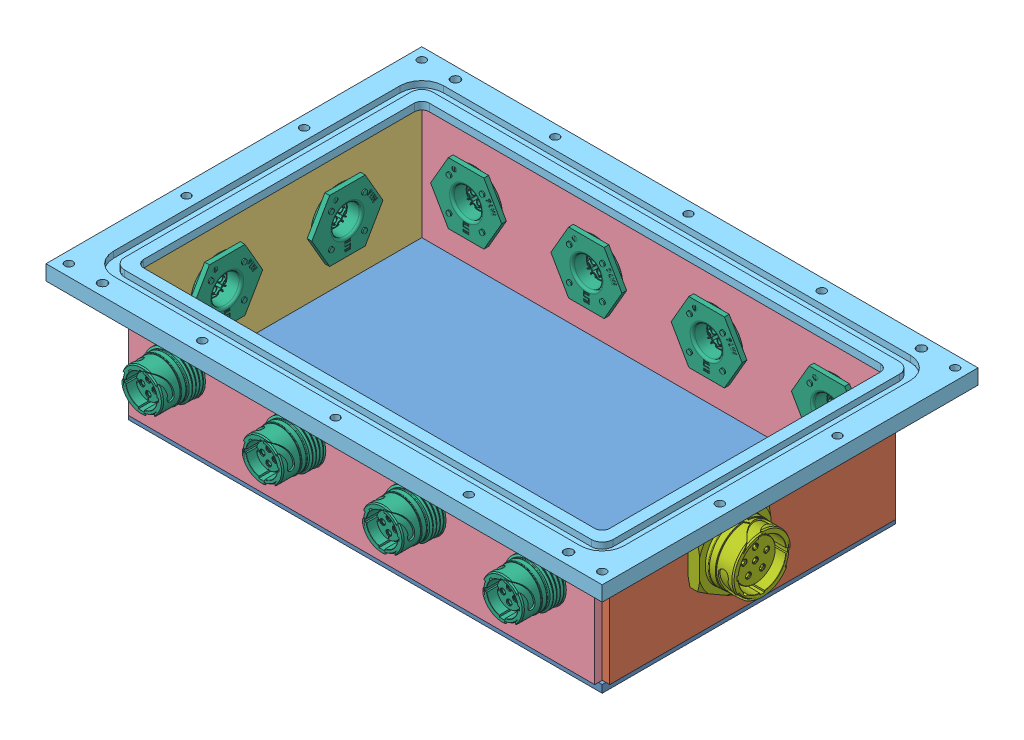
SolidWorks assembly A. Power Distribution Box Welded, configuration Default. Lengths in mm.
Overall size (237.68 57.15 161.39).
17 component instances, 7 part files, 46 mates.
Components (placement in the parent):
- Power Distribution Box Bottom-1: Power Distribution Box Bottom [Default] at (106.4097 88.1405 149.8512) size (200.03 6.35 123.83)
- Power Distribution Box Front Plate-1: Power Distribution Box Front Plate [Default] at (306.4347 91.3155 149.8512) size (3.17 50.8 120.65)
- Power Distribution Box Back Plate-1: Power Distribution Box Back Plate [Default] at (-93.6153 91.3155 149.8512) size (3.17 50.8 120.65)
- Power Distribution Box Side Plate-1: Power Distribution Box Side Plate [Default] at (106.4097 91.3155 149.8512) size (196.85 50.8 3.18)
- Power Distribution Box Side Plate-2: Power Distribution Box Side Plate [Default] at (106.4097 91.3155 26.0262) size (196.85 50.8 3.18)
- Power Distribution Box Flange-1: Power Distribution Box Flange [Default] at (106.4097 138.9405 149.8512) size (234.95 6.35 158.75)
- Samtec ACR 16 Recepticle-1: Samtec ACR 16 Recepticle [Default] at (30.2097 119.8905 230.1762) x (-1 0 0) z (0 0 1) size (30.02 26 24.37)
- Samtec ACR 16 Recepticle-2: Samtec ACR 16 Recepticle [Default] at (-12.0153 119.8905 175.2512) x (0 0 -1) z (-1 0 0) size (30.02 26 24.37)
- Samtec ACR 16 Recepticle-3: Samtec ACR 16 Recepticle [Default] at (30.2097 119.8905 69.5262) x (1 0 0) z (0 0 -1) size (30.02 26 24.37)
- Samtec ACR 16 Recepticle-4: Samtec ACR 16 Recepticle [Default] at (81.0097 119.8905 230.1762) x (-1 0 0) z (0 0 1) size (30.02 26 24.37)
- Samtec ACR 16 Recepticle-5: Samtec ACR 16 Recepticle [Default] at (131.8097 119.8905 230.1762) x (-1 0 0) z (0 0 1) size (30.02 26 24.37)
- Samtec ACR 16 Recepticle-6: Samtec ACR 16 Recepticle [Default] at (182.6097 119.8905 230.1762) x (-1 0 0) z (0 0 1) size (30.02 26 24.37)
- Samtec ACR 16 Recepticle-7: Samtec ACR 16 Recepticle [Default] at (81.0097 119.8905 69.5262) x (1 0 0) z (0 0 -1) size (30.02 26 24.37)
- Samtec ACR 16 Recepticle-8: Samtec ACR 16 Recepticle [Default] at (131.8097 119.8905 69.5262) x (1 0 0) z (0 0 -1) size (30.02 26 24.37)
- Samtec ACR 16 Recepticle-9: Samtec ACR 16 Recepticle [Default] at (182.6097 119.8905 69.5262) x (1 0 0) z (0 0 -1) size (30.02 26 24.37)
- Samtec ACR 16 Recepticle-10: Samtec ACR 16 Recepticle [Default] at (-12.0153 119.8905 124.4512) x (0 0 -1) z (-1 0 0) size (30.02 26 24.37)
- Samtec ACR 22-1: Samtec ACR 22 [Default] at (224.8347 119.8905 162.5512) x (0 0 -1) z (1 0 0) size (38.11 34.64 24.46)
Mates (geometry in assembly coordinates):
- Coincident1: coincident anti-aligned: plane of Power Distribution Box Bottom-1 through (204.8347 94.4905 210.1762) normal (1 0 0); plane of Power Distribution Box Front Plate-1 through (204.8347 142.1155 210.1762) normal (-1 0 0)
- Coincident2: coincident anti-aligned: plane of Power Distribution Box Bottom-1 through (106.4097 91.3155 149.8512) normal (0 1 0); plane of Power Distribution Box Front Plate-1 through (306.4347 91.3155 149.8512) normal (0 -1 0)
- Coincident3: coincident anti-aligned: plane of Power Distribution Box Side Plate-2 through (106.4097 91.3155 26.0262) normal (0 -1 0); plane of Power Distribution Box Bottom-1 through (106.4097 91.3155 149.8512) normal (0 1 0)
- Coincident4: coincident anti-aligned: plane of Power Distribution Box Bottom-1 through (204.8347 94.4905 89.5262) normal (0 0 -1); plane of Power Distribution Box Side Plate-2 through (208.0097 142.1155 89.5262) normal (0 0 1)
- Coincident5: coincident anti-aligned: line of Power Distribution Box Front Plate-1 through (204.8347 142.1155 89.5262) axis (0 -1 0); line of Power Distribution Box Side Plate-2 through (204.8347 91.3155 89.5262) axis (0 1 0)
- Coincident6: coincident anti-aligned: line of Power Distribution Box Back Plate-1 through (7.9847 142.1155 89.5262) axis (0 -1 0); line of Power Distribution Box Side Plate-2 through (7.9847 91.3155 89.5262) axis (0 1 0)
- Coincident7: coincident anti-aligned: plane of Power Distribution Box Bottom-1 through (106.4097 91.3155 149.8512) normal (0 1 0); plane of Power Distribution Box Back Plate-1 through (-93.6153 91.3155 149.8512) normal (0 -1 0)
- Coincident8: coincident anti-aligned: plane of Power Distribution Box Bottom-1 through (7.9847 94.4905 89.5262) normal (-1 0 0); plane of Power Distribution Box Back Plate-1 through (7.9847 142.1155 210.1762) normal (1 0 0)
- Coincident9: coincident anti-aligned: line of Power Distribution Box Back Plate-1 through (7.9847 142.1155 210.1762) axis (0 -1 0); line of Power Distribution Box Side Plate-1 through (7.9847 91.3155 210.1762) axis (0 1 0)
- Coincident10: coincident anti-aligned: plane of Power Distribution Box Bottom-1 through (106.4097 91.3155 149.8512) normal (0 1 0); plane of Power Distribution Box Side Plate-1 through (106.4097 91.3155 149.8512) normal (0 -1 0)
- Coincident11: coincident anti-aligned: plane of Power Distribution Box Bottom-1 through (7.9847 94.4905 210.1762) normal (0 0 1); plane of Power Distribution Box Side Plate-1 through (7.9847 91.3155 210.1762) normal (0 0 -1)
- Coincident12: coincident anti-aligned: plane of Power Distribution Box Side Plate-1 through (106.4097 142.1155 149.8512) normal (0 1 0); plane of Power Distribution Box Flange-1 through (106.4097 142.1155 149.8512) normal (0 -1 0)
- Coincident13: coincident anti-aligned: plane of Power Distribution Box Side Plate-1 through (208.0097 142.1155 213.3512) normal (0 0 1); plane of Power Distribution Box Flange-1 through (208.0097 142.1155 213.3512) normal (0 0 -1)
- Coincident14: coincident anti-aligned: plane of Power Distribution Box Back Plate-1 through (4.8097 91.3155 207.0012) normal (-1 0 0); plane of Power Distribution Box Flange-1 through (4.8097 142.1155 213.3512) normal (1 0 0)
- Concentric6: concentric anti-aligned: cylinder of Power Distribution Box Side Plate-1 through (30.2097 119.8905 86.3512) axis (0 0 1) radius 10.2489; cylinder of Samtec ACR 16 Recepticle-1 through (30.2097 119.8905 230.1762) axis (0 0 -1) radius 8.75
- Parallel4: parallel anti-aligned: plane of Power Distribution Box Side Plate-1 through (106.4097 111.1529 86.3512) normal (0 1 0); plane of Samtec ACR 16 Recepticle-1 through (34.7677 111.1405 230.5464) normal (0 -1 0)
- Tangent2: tangent: plane of Power Distribution Box Side Plate-1 through (7.9847 91.3155 210.1762) normal (0 0 -1); torus of Samtec ACR 16 Recepticle-1
- Concentric8: concentric aligned: cylinder of Power Distribution Box Back Plate-1 through (-195.2163 119.8905 175.2512) axis (1 0 0) radius 10.2489; cylinder of Samtec ACR 16 Recepticle-2 through (-12.0153 119.8905 175.2512) axis (1 0 0) radius 8.75
- Parallel6: parallel anti-aligned: plane of Power Distribution Box Back Plate-1 through (-195.2163 111.1529 149.8512) normal (0 1 0); plane of Samtec ACR 16 Recepticle-2 through (-12.3855 111.1405 179.8092) normal (0 -1 0)
- Tangent4: tangent: plane of Power Distribution Box Back Plate-1 through (7.9847 142.1155 210.1762) normal (1 0 0); torus of Samtec ACR 16 Recepticle-2
- Concentric9: concentric aligned: cylinder of Power Distribution Box Side Plate-2 through (30.2097 119.8905 -37.4738) axis (0 0 1) radius 10.2489; cylinder of Samtec ACR 16 Recepticle-3 through (30.2097 119.8905 69.5262) axis (0 0 1) radius 8.75
- Parallel7: parallel anti-aligned: plane of Power Distribution Box Side Plate-2 through (106.4097 111.1529 -37.4738) normal (0 1 0); plane of Samtec ACR 16 Recepticle-3 through (25.6517 111.1405 69.1559) normal (0 -1 0)
- Tangent5: tangent: plane of Power Distribution Box Side Plate-2 through (208.0097 142.1155 89.5262) normal (0 0 1); torus of Samtec ACR 16 Recepticle-3
- Concentric10: concentric anti-aligned: cylinder of Power Distribution Box Side Plate-1 through (81.0097 119.8905 86.3512) axis (0 0 1) radius 10.2489; cylinder of Samtec ACR 16 Recepticle-4 through (81.0097 119.8905 230.1762) axis (0 0 -1) radius 8.75
- Parallel8: parallel anti-aligned: plane of Power Distribution Box Side Plate-1 through (106.4097 111.1529 86.3512) normal (0 1 0); plane of Samtec ACR 16 Recepticle-4 through (85.5677 111.1405 230.5464) normal (0 -1 0)
- Tangent6: tangent: plane of Power Distribution Box Side Plate-1 through (7.9847 91.3155 210.1762) normal (0 0 -1); torus of Samtec ACR 16 Recepticle-4
- Tangent7: tangent: plane of Power Distribution Box Side Plate-1 through (7.9847 91.3155 210.1762) normal (0 0 -1); torus of Samtec ACR 16 Recepticle-5
- Concentric11: concentric anti-aligned: cylinder of Power Distribution Box Side Plate-1 through (131.8097 119.8905 86.3512) axis (0 0 1) radius 10.2489; cylinder of Samtec ACR 16 Recepticle-5 through (131.8097 119.8905 230.1762) axis (0 0 -1) radius 8.75
- Parallel9: parallel anti-aligned: plane of Power Distribution Box Side Plate-1 through (106.4097 111.1529 86.3512) normal (0 1 0); plane of Samtec ACR 16 Recepticle-5 through (136.3677 111.1405 230.5464) normal (0 -1 0)
- Tangent8: tangent: plane of Power Distribution Box Side Plate-1 through (7.9847 91.3155 210.1762) normal (0 0 -1); torus of Samtec ACR 16 Recepticle-6
- Concentric12: concentric anti-aligned: cylinder of Power Distribution Box Side Plate-1 through (182.6097 119.8905 86.3512) axis (0 0 1) radius 10.2489; cylinder of Samtec ACR 16 Recepticle-6 through (182.6097 119.8905 230.1762) axis (0 0 -1) radius 8.75
- Parallel10: parallel anti-aligned: plane of Power Distribution Box Side Plate-1 through (106.4097 111.1529 86.3512) normal (0 1 0); plane of Samtec ACR 16 Recepticle-6 through (187.1677 111.1405 230.5464) normal (0 -1 0)
- Concentric13: concentric aligned: cylinder of Power Distribution Box Side Plate-2 through (81.0097 119.8905 -37.4738) axis (0 0 1) radius 10.2489; cylinder of Samtec ACR 16 Recepticle-7 through (81.0097 119.8905 69.5262) axis (0 0 1) radius 8.75
- Parallel11: parallel anti-aligned: plane of Power Distribution Box Side Plate-2 through (106.4097 111.1529 -37.4738) normal (0 1 0); plane of Samtec ACR 16 Recepticle-7 through (76.4517 111.1405 69.1559) normal (0 -1 0)
- Tangent9: tangent: plane of Power Distribution Box Side Plate-2 through (208.0097 142.1155 89.5262) normal (0 0 1); torus of Samtec ACR 16 Recepticle-7
- Tangent10: tangent: plane of Power Distribution Box Side Plate-2 through (208.0097 142.1155 89.5262) normal (0 0 1); torus of Samtec ACR 16 Recepticle-8
- Concentric14: concentric aligned: cylinder of Power Distribution Box Side Plate-2 through (131.8097 119.8905 -37.4738) axis (0 0 1) radius 10.2489; cylinder of Samtec ACR 16 Recepticle-8 through (131.8097 119.8905 69.5262) axis (0 0 1) radius 8.75
- Parallel12: parallel anti-aligned: plane of Power Distribution Box Side Plate-2 through (106.4097 111.1529 -37.4738) normal (0 1 0); plane of Samtec ACR 16 Recepticle-8 through (127.2517 111.1405 69.1559) normal (0 -1 0)
- Tangent11: tangent: plane of Power Distribution Box Side Plate-2 through (208.0097 142.1155 89.5262) normal (0 0 1); torus of Samtec ACR 16 Recepticle-9
- Concentric15: concentric aligned: cylinder of Power Distribution Box Side Plate-2 through (182.6097 119.8905 -37.4738) axis (0 0 1) radius 10.2489; cylinder of Samtec ACR 16 Recepticle-9 through (182.6097 119.8905 69.5262) axis (0 0 1) radius 8.75
- Parallel13: parallel anti-aligned: plane of Power Distribution Box Side Plate-2 through (106.4097 111.1529 -37.4738) normal (0 1 0); plane of Samtec ACR 16 Recepticle-9 through (178.0517 111.1405 69.1559) normal (0 -1 0)
- Concentric16: concentric aligned: cylinder of Power Distribution Box Back Plate-1 through (-195.2163 119.8905 124.4512) axis (1 0 0) radius 10.2489; cylinder of Samtec ACR 16 Recepticle-10 through (-12.0153 119.8905 124.4512) axis (1 0 0) radius 8.75
- Parallel14: parallel anti-aligned: plane of Power Distribution Box Back Plate-1 through (-195.2163 111.1529 149.8512) normal (0 1 0); plane of Samtec ACR 16 Recepticle-10 through (-12.3855 111.1405 129.0092) normal (0 -1 0)
- Tangent12: tangent: plane of Power Distribution Box Back Plate-1 through (7.9847 142.1155 210.1762) normal (1 0 0); torus of Samtec ACR 16 Recepticle-10
- Concentric17: concentric anti-aligned: cylinder of Power Distribution Box Front Plate-1 through (408.0357 119.8905 162.5512) axis (-1 0 0) radius 12.5539; cylinder of Samtec ACR 22-1 through (224.8347 119.8905 162.5512) axis (1 0 0) radius 12.554
- Tangent13: tangent: plane of Power Distribution Box Front Plate-1 through (204.8347 142.1155 210.1762) normal (-1 0 0); torus of Samtec ACR 22-1
